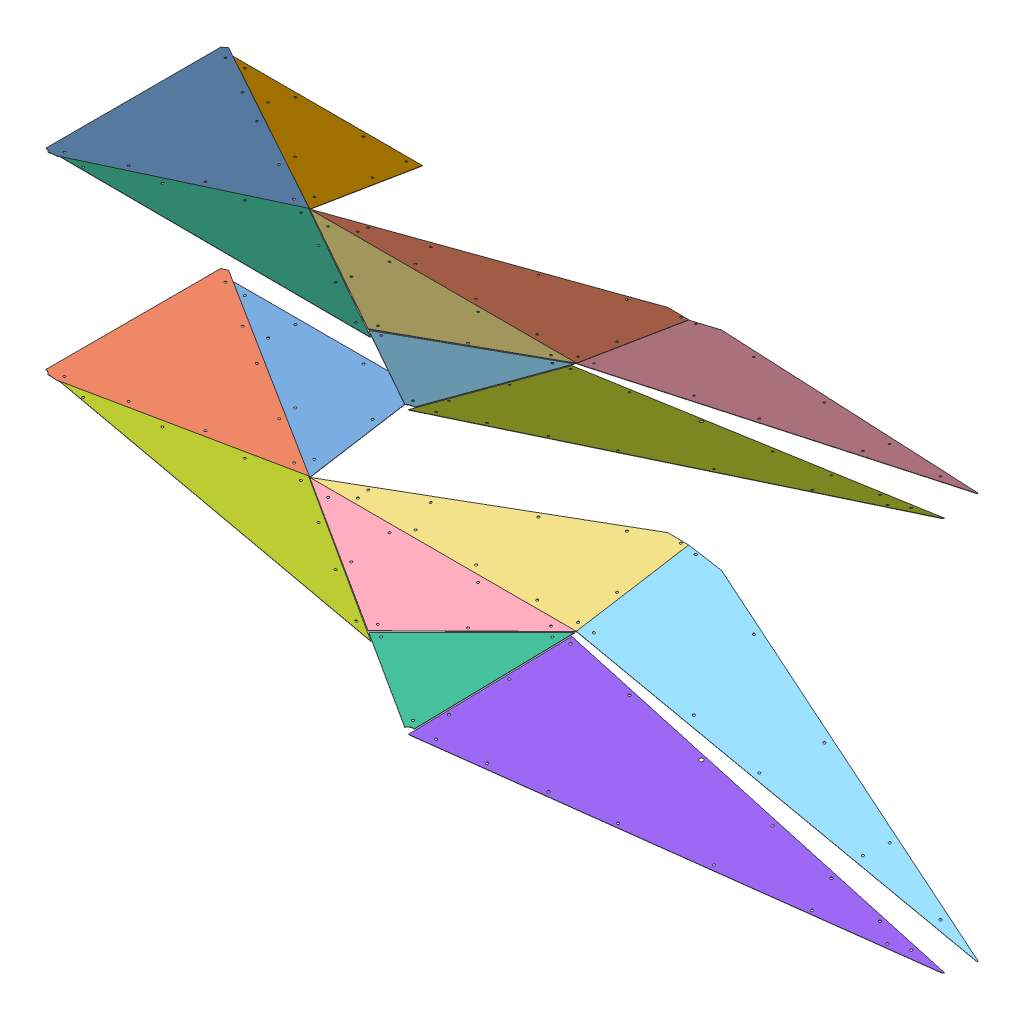
SolidWorks assembly PUTM-F-MS-CO, configuration Domyślna. Lengths in mm.
Overall size (1567.5 729.74 481.8).
16 component instances, 16 part files, 0 mates.
Components (placement in the parent):
- PUTM-F-MS-CO-1^PUTM-F-MS-CO-1: PUTM-F-MS-CO-1^PUTM-F-MS-CO [Domyślna] at origin size (340.96 34.07 202.82) (virtual)
- PUTM-F-MS-CO-2^PUTM-F-MS-CO-1: PUTM-F-MS-CO-2^PUTM-F-MS-CO [Domyślna] at (-24.2849 -246.6158 0) x (0.995187 -0.097999 0) z (0.097999 0.995187 0) size (368.65 324.83 0.5) (virtual)
- PUTM-F-MS-CO-3^PUTM-F-MS-CO-3: PUTM-F-MS-CO-3^PUTM-F-MS-CO [Domyślna] at origin size (479.7 34.02 202.5) (virtual)
- PUTM-F-MS-CO-4^PUTM-F-MS-CO-1: PUTM-F-MS-CO-4^PUTM-F-MS-CO [Domyślna] at origin size (480 26.59 160.26) (virtual)
- PUTM-F-MS-CO-7^PUTM-F-MS-CO-1: PUTM-F-MS-CO-7^PUTM-F-MS-CO [Domyślna] at origin size (719.06 190.01 204.04) (virtual)
- PUTM-F-MS-CO-8^PUTM-F-MS-CO-1: PUTM-F-MS-CO-8^PUTM-F-MS-CO [Domyślna] at origin size (211.23 42.47 257.72) (virtual)
- PUTM-F-MS-CO-10^PUTM-F-MS-CO-1: PUTM-F-MS-CO-10^PUTM-F-MS-CO [Domyślna] at origin size (623.05 61.85 173.21) (virtual)
- putm-f-ms-co-6^PUTM-F-MS-CO-2: putm-f-ms-co-6^PUTM-F-MS-CO [Domyślna] at origin size (752.11 143.72 257.63) (virtual)
- MirrorPUTM-F-MS-CO-1^PUTM-F-MS-CO-3: MirrorPUTM-F-MS-CO-1^PUTM-F-MS-CO [Domyślna] x (1 0 0) z (0 0 -1) size (340.96 34.07 202.82) (virtual)
- MirrorPUTM-F-MS-CO-2^PUTM-F-MS-CO-3: MirrorPUTM-F-MS-CO-2^PUTM-F-MS-CO [Domyślna] at (-24.2849 246.6158 0) x (0.995187 0.097999 0) z (-0.097999 0.995187 0) size (368.65 324.83 0.5) (virtual)
- MirrorPUTM-F-MS-CO-3^PUTM-F-MS-CO-5: MirrorPUTM-F-MS-CO-3^PUTM-F-MS-CO [Domyślna] x (1 0 0) z (0 0 -1) size (479.7 34.02 202.5) (virtual)
- MirrorPUTM-F-MS-CO-4^PUTM-F-MS-CO-3: MirrorPUTM-F-MS-CO-4^PUTM-F-MS-CO [Domyślna] x (1 0 0) z (0 0 -1) size (480 26.59 160.26) (virtual)
- MirrorPUTM-F-MS-CO-7^PUTM-F-MS-CO-3: MirrorPUTM-F-MS-CO-7^PUTM-F-MS-CO [Domyślna] x (1 0 0) z (0 0 -1) size (719.06 190.01 204.04) (virtual)
- MirrorPUTM-F-MS-CO-8^PUTM-F-MS-CO-3: MirrorPUTM-F-MS-CO-8^PUTM-F-MS-CO [Domyślna] x (1 0 0) z (0 0 -1) size (211.23 42.47 257.72) (virtual)
- MirrorPUTM-F-MS-CO-10^PUTM-F-MS-CO-3: MirrorPUTM-F-MS-CO-10^PUTM-F-MS-CO [Domyślna] x (1 0 0) z (0 0 -1) size (623.05 61.85 173.21) (virtual)
- MirrorPUTM-F-MS-CO-6^PUTM-F-MS-CO-3: MirrorPUTM-F-MS-CO-6^PUTM-F-MS-CO [Domyślna] x (1 0 0) z (0 0 -1) size (752.11 143.72 257.63) (virtual)
